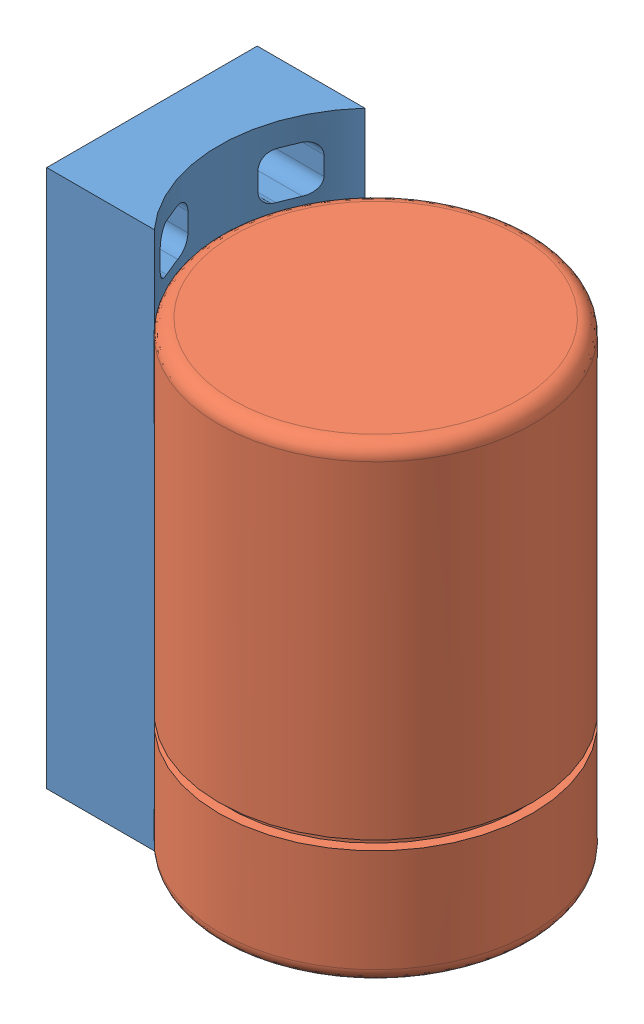
SolidWorks assembly Can Grabber, configuration Default. Lengths in mm.
Overall size (81.47 115 67).
2 component instances, 2 part files, 0 mates.
Components (placement in the parent):
- Magnet Block-1: Magnet Block [Default] at origin size (23 115 45)
- Can-1: Can [Default] at (47.9738 -57.4929 0.154) size (67 100 67)
